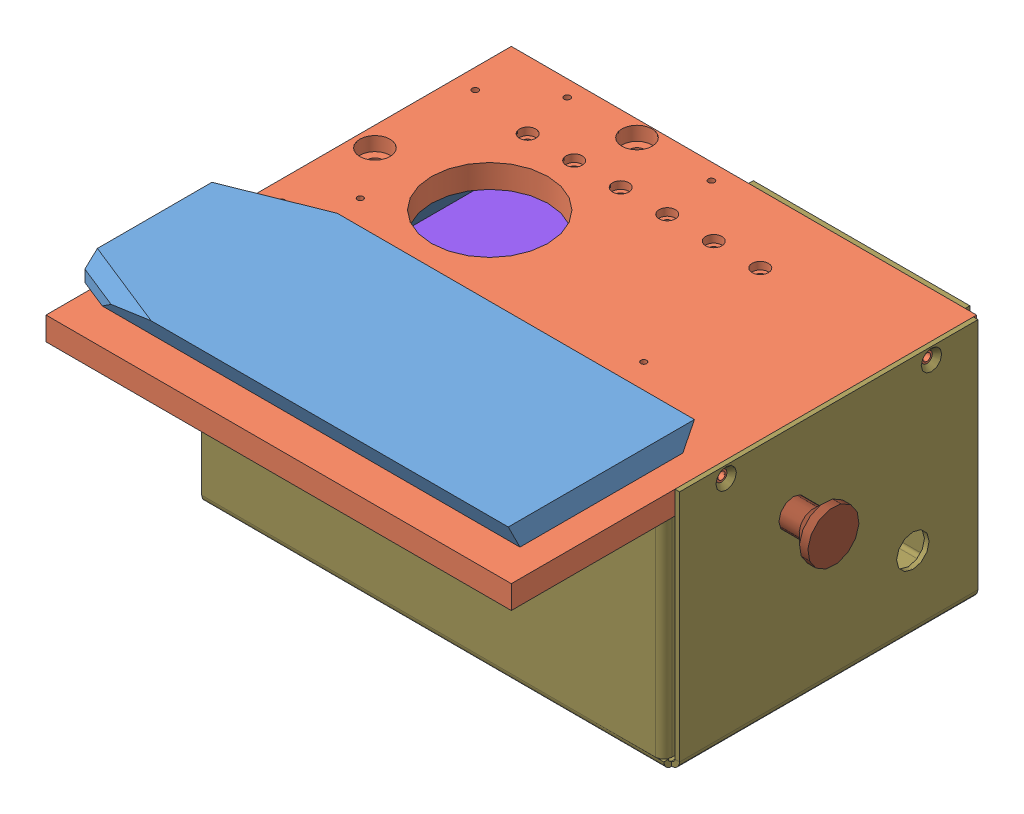
SolidWorks assembly dichroic assembly without cubes, configuration Default. Lengths in mm.
Overall size (111.49 57 101).
20 component instances, 13 part files, 42 mates.
Components (placement in the parent):
- Olympus bottom dovetail slider1-1: Olympus bottom dovetail slider1 [Default] at (-24.3795 51.0731 92.1913) size (96 5 40)
- dichroic insert plate-1: dichroic insert plate [Default] at (27.4955 46.0731 67.419) size (100 5 100)
- step_87208.step-1: step_87208.step [Default] at (29.9402 0.9731 50.189) x (0 0 -1) z (0 1 0) size (58.01 191.73 33.28) (hidden)
- 32513-1: 32513 [Default] at (6.6137 26.2407 49.7946) x (1 0 0) z (0 -0.707107 0.707107) size (25 5 35)
- aperture holder front-1: aperture holder front [Default] at (30.9955 30.4358 24.419) x (0 0 -1) z (-1 0 0) size (7 46 45)
- aperture holder back-1: aperture holder back [Default] at (-14.0045 30.4358 75.959) x (0 0 1) z (1 0 0) size (7 46 45)
- linear guide-1: linear guide [Default] at (50.4955 44.8731 31.919) x (0 0 -1) z (-1 0 0) size (8 4 60) (flexible)
  - linear guide rail-1: linear guide rail [Default] at origin size (3 2.4 60)
  - linear guide rider-1: linear guide rider [Default] at (0 1.3 28.7818) size (8 3 15.5)
  - linear guide rider-2: linear guide rider [Default] at (0 1.3 45.2818) size (8 3 15.5)
- linear guide-2: linear guide [Default] at (50.4955 44.8731 70.919) x (0 0 -1) z (-1 0 0) size (8 4 60) (flexible)
  - linear guide rail-1: linear guide rail [Default] at origin size (3 2.4 60)
  - linear guide rider-1: linear guide rider [Default] at (0 1.3 28.7818) size (8 3 15.5)
  - linear guide rider-2: linear guide rider [Default] at (0 1.3 45.2818) size (8 3 15.5)
- mirror holder for rider-1: mirror holder for rider [Default] at (19.1137 19.454 11.6211) x (0 0 1) z (-1 0 0) size (50.45 31.47 28)
- magnet holder-1: magnet holder [Default] at (-10.0045 46.0731 61.919) x (0 0 -1) z (-1 0 0) size (7 5 5)
- magnet holder-2: magnet holder [Default] at (49.9955 46.0731 61.919) x (0 0 1) z (1 0 0) size (7 5 5)
- side panel-1: side panel [Default] at (-19.0045 23.0731 50.189) x (0 0 1) z (-1 0 0) size (65.54 46 13.5)
- rod-1: rod [Default] at (51.7486 34.8731 57.819) x (-1 0 0) z (0 -0.364341 0.931266) size (75.29 11 11)
- slider lid-1: slider lid [Default] at (27.4955 0.0731 50.189) x (1 0 0) z (0 1 0) size (101 67.54 52)
Mates (geometry in assembly coordinates):
- Angle2: planar angle = 0.785398 rad anti-aligned: plane of dichroic insert plate-1 through (27.4955 46.0731 67.419) normal (0 -1 0); plane of 32513-1 through (-5.8863 42.1506 40.9558) normal (0 0.707107 -0.707107)
- Coincident23: coincident anti-aligned: plane of dichroic insert plate-1 through (27.4955 46.0731 67.419) normal (0 -1 0); plane of aperture holder front-1 through (-14.0045 46.0731 24.419) normal (0 1 0)
- Parallel4: parallel aligned: plane of dichroic insert plate-1 through (-22.5045 51.0731 17.419) normal (0 0 -1); plane of aperture holder front-1 through (-14.0045 46.0731 17.419) normal (0 0 -1)
- Coincident24: coincident aligned: plane of dichroic insert plate-1 through (-22.5045 51.0731 17.419) normal (0 0 -1); plane of aperture holder front-1 through (-14.0045 46.0731 17.419) normal (0 0 -1)
- Coincident26: coincident anti-aligned: plane of dichroic insert plate-1 through (27.4955 46.0731 67.419) normal (0 -1 0); plane of aperture holder back-1 through (30.9955 46.0731 75.959) normal (0 1 0)
- Parallel5: parallel aligned: plane of dichroic insert plate-1 through (-22.5045 51.0731 117.419) normal (0 0 1); plane of aperture holder back-1 through (30.9955 46.0731 82.959) normal (0 0 1)
- Coincident28: coincident anti-aligned: plane of step_87208.step-1 through (-19.4098 6.6731 79.189) normal (0 0 1); plane of aperture holder back-1 through (30.9955 0.0731 79.189) normal (0 0 -1)
- Coincident29: coincident anti-aligned: plane of step_87208.step-1 through (5.9402 0.5731 21.189) normal (0 0 -1); plane of aperture holder front-1 through (-14.0045 0.0731 21.189) normal (0 0 1)
- Coincident30: coincident anti-aligned: plane of dichroic insert plate-1 through (27.4955 46.0731 67.419) normal (0 -1 0); plane of linear guide-1/linear guide rail-1 through (-9.5045 46.0731 33.219) normal (0 1 0)
- Parallel6: parallel aligned: plane of dichroic insert plate-1 through (-22.5045 51.0731 17.419) normal (0 0 -1); plane of linear guide-1/linear guide rail-1 through (-9.5045 45.8731 30.419) normal (0 0 -1)
- Coincident31: coincident aligned: plane of linear guide-1/linear guide rail-1 through (-9.5045 44.2731 30.419) normal (-1 0 0); plane of linear guide-2/linear guide rail-1 through (-9.5045 44.2731 69.419) normal (-1 0 0)
- Coincident32: coincident aligned: plane of linear guide-1/linear guide rider-1 through (24.1137 43.5731 31.919) normal (1 0 0); plane of linear guide-2/linear guide rider-1 through (24.1137 43.5731 70.919) normal (1 0 0)
- Distance3: distance = 36 mm anti-aligned: plane of linear guide-2/linear guide rail-1 through (-9.5045 45.8731 69.419) normal (0 0 -1); plane of linear guide-1/linear guide rail-1 through (-9.5045 45.8731 33.419) normal (0 0 1)
- Distance4: distance = 13 mm aligned: plane of linear guide-1/linear guide rail-1 through (-9.5045 45.8731 30.419) normal (0 0 -1); plane of dichroic insert plate-1 through (-22.5045 51.0731 17.419) normal (0 0 -1)
- Coincident33: coincident anti-aligned: plane of dichroic insert plate-1 through (27.4955 46.0731 67.419) normal (0 -1 0); plane of linear guide-2/linear guide rail-1 through (-9.5045 46.0731 72.219) normal (0 1 0)
- Parallel7: parallel aligned: plane of dichroic insert plate-1 through (-22.5045 51.0731 17.419) normal (0 0 -1); plane of mirror holder for rider-1 through (-5.8863 38.5603 25.319) normal (0 0 -1)
- Coincident34: coincident anti-aligned: plane of linear guide-1/linear guide rider-2 through (-5.4863 42.0731 35.919) normal (0 -1 0); plane of mirror holder for rider-1 through (-5.8863 42.0731 27.819) normal (0 1 0)
- Coincident37: coincident aligned: plane of 32513-1 through (-5.8863 17.4019 65.7045) normal (-1 0 0); plane of mirror holder for rider-1 through (-5.8863 19.454 11.6211) normal (-1 0 0)
- Coincident38: coincident anti-aligned: plane of dichroic insert plate-1 through (27.4955 46.0731 67.419) normal (0 -1 0); plane of magnet holder-1 through (-10.0045 46.0731 61.919) normal (0 1 0)
- Distance5: distance = 10 mm: line of magnet holder-1 through (-12.5045 41.0731 65.419) axis (0 0 -1); plane of dichroic insert plate-1 through (-22.5045 51.0731 117.419) normal (-1 0 0)
- Coincident40: coincident anti-aligned: plane of dichroic insert plate-1 through (27.4955 46.0731 67.419) normal (0 -1 0); plane of magnet holder-2 through (49.9955 46.0731 61.919) normal (0 1 0)
- Parallel8: parallel aligned: plane of dichroic insert plate-1 through (77.4955 51.0731 117.419) normal (1 0 0); plane of magnet holder-2 through (52.4955 41.0731 58.419) normal (1 0 0)
- Distance7: distance = 41 mm aligned: plane of magnet holder-1 through (-12.5045 41.0731 58.419) normal (0 0 -1); plane of dichroic insert plate-1 through (-22.5045 51.0731 17.419) normal (0 0 -1)
- Coincident42: coincident aligned: plane of magnet holder-1 through (-12.5045 41.0731 58.419) normal (0 0 -1); plane of magnet holder-2 through (52.4955 41.0731 58.419) normal (0 0 -1)
- Distance8: distance = 70 mm aligned: plane of magnet holder-2 through (47.4955 41.0731 58.419) normal (-1 0 0); plane of dichroic insert plate-1 through (-22.5045 51.0731 117.419) normal (-1 0 0)
- Coincident44: coincident anti-aligned: plane of dichroic insert plate-1 through (27.4955 46.0731 67.419) normal (0 -1 0); plane of side panel-1 through (-22.5045 46.0731 17.419) normal (0 1 0)
- Coincident45: coincident aligned: plane of aperture holder front-1 through (-14.0045 46.0731 17.419) normal (0 0 -1); plane of side panel-1 through (-22.5045 46.0731 17.419) normal (0 0 -1)
- Coincident48: coincident anti-aligned: plane of side panel-1 through (-22.5045 0.0731 17.419) normal (0 -1 0); plane of slider lid-1 through (27.4955 0.0731 50.189) normal (0 1 0)
- Coincident49: coincident anti-aligned: plane of dichroic insert plate-1 through (-22.5045 51.0731 17.419) normal (0 0 -1); plane of slider lid-1 through (27.4955 0.0731 17.419) normal (0 0 1)
- Coincident50: coincident aligned: plane of side panel-1 through (-22.5045 23.0731 50.189) normal (-1 0 0); plane of slider lid-1 through (-22.5045 -0.9269 82.959) normal (-1 0 0)
- Concentric3: concentric aligned: cylinder of mirror holder for rider-1 through (22.1137 34.8731 57.819) axis (1 0 0) radius 1.65; cylinder of rod-1 through (98.5393 34.8731 57.819) axis (1 0 0) radius 3
- Distance11: distance = 65 mm aligned: plane of mirror holder for rider-1 through (22.1137 19.454 11.6211) normal (1 0 0); plane of rod-1 through (87.1137 29.7511 55.8151) normal (1 0 0)
- Distance12: distance = 0.1 mm anti-aligned: plane of mirror holder for rider-1 through (-5.8863 42.0731 75.019) normal (0 0 -1); plane of linear guide-2/linear guide rider-2 through (-7.8863 45.0731 74.919) normal (0 0 1)
- Coincident51: coincident anti-aligned: plane of step_87208.step-1 through (19.5402 8.0731 50.189) normal (0 1 0); plane of aperture holder front-1 through (-14.0045 8.0731 21.189) normal (0 -1 0)
- Coincident52: coincident anti-aligned: plane of aperture holder back-1 through (-14.0045 30.4358 75.959) normal (-1 0 0); plane of side panel-1 through (-14.0045 23.0731 50.189) normal (1 0 0)
- Coincident54: coincident aligned: plane of dichroic insert plate-1 through (-22.5045 51.0731 117.419) normal (-1 0 0); plane of side panel-1 through (-22.5045 23.0731 50.189) normal (-1 0 0)
- Coincident55: coincident anti-aligned: plane of aperture holder front-1 through (-14.0045 30.4358 24.419) normal (-1 0 0); plane of side panel-1 through (-14.0045 23.0731 50.189) normal (1 0 0)
- Distance13: distance = 13 mm: plane of linear guide-2/linear guide rail-1 through (-9.5045 44.2731 69.419) normal (-1 0 0); line of side panel-1 through (-22.5045 46.0731 82.959) axis (0 0 -1)
- Distance14: distance = 2 mm aligned: plane of mirror holder for rider-1 through (-5.8863 19.454 11.6211) normal (-1 0 0); plane of linear guide-2/linear guide rider-2 through (-7.8863 43.5731 70.919) normal (-1 0 0)
- Distance15: distance = 2 mm aligned: plane of mirror holder for rider-1 through (22.1137 19.454 11.6211) normal (1 0 0); plane of linear guide-2/linear guide rider-1 through (24.1137 43.5731 70.919) normal (1 0 0)
- Coincident57: coincident aligned: plane of linear guide-1/linear guide rider-2 through (-7.8863 43.5731 31.919) normal (-1 0 0); plane of linear guide-2/linear guide rider-2 through (-7.8863 43.5731 70.919) normal (-1 0 0)
- Coincident58: coincident aligned: plane of linear guide-1/linear guide rider-1 through (24.1137 43.5731 31.919) normal (1 0 0); plane of linear guide-2/linear guide rider-1 through (24.1137 43.5731 70.919) normal (1 0 0)
